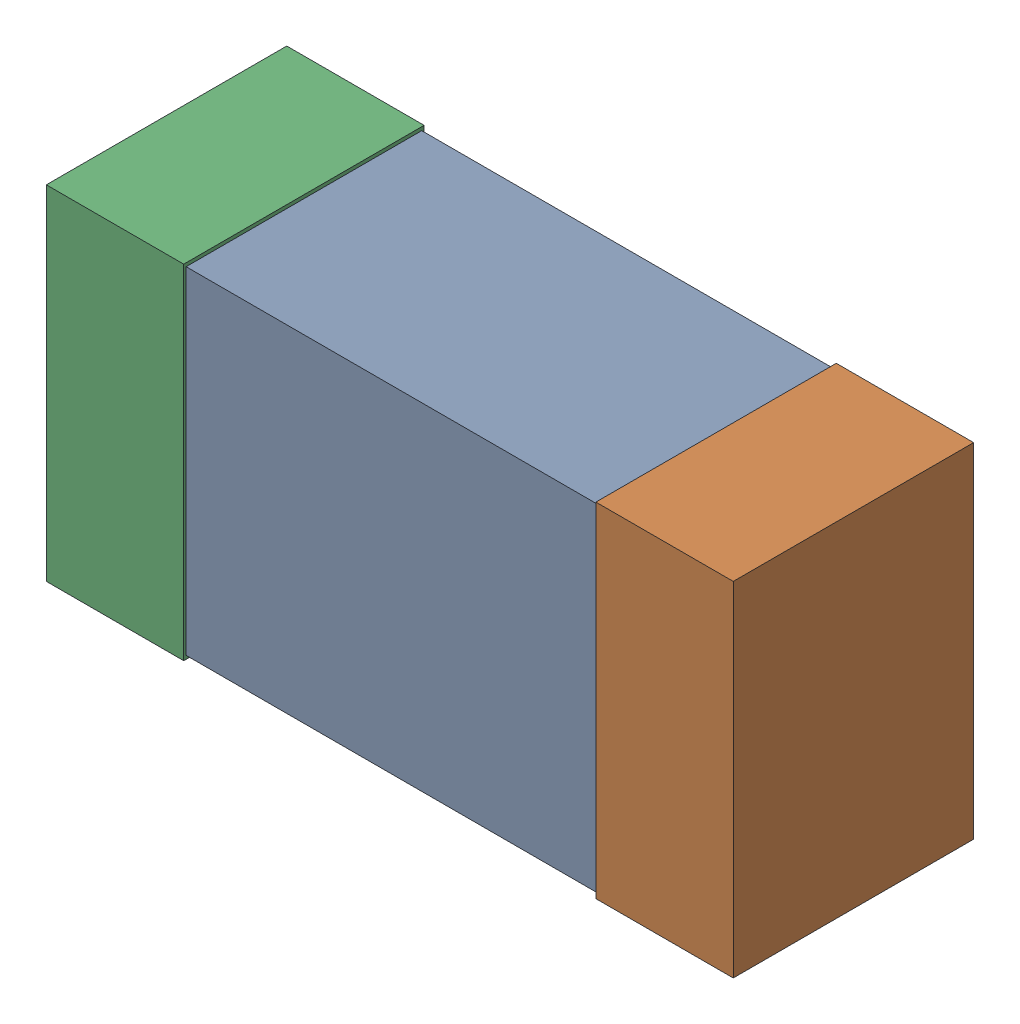
SolidWorks assembly R3, configuration Predeterminado. Lengths in mm.
Overall size (1 0.5 0.35).
4 component instances, 3 part files, 0 mates.
Components (placement in the parent):
- 6074689360-1: 6074689360 [Predeterminado] at (30.5 41.5 0) size (1 0.5 0.35)
  - body-1-1: body-1 [Predeterminado] at (-0.3 -0.245 0.0035) size (0.6 0.49 0.34)
  - term2-1: term2 [Predeterminado] at (0.3 -0.25 0) size (0.2 0.5 0.35)
  - term1-1: term1 [Predeterminado] at (-0.5 -0.25 0) size (0.2 0.5 0.35)
